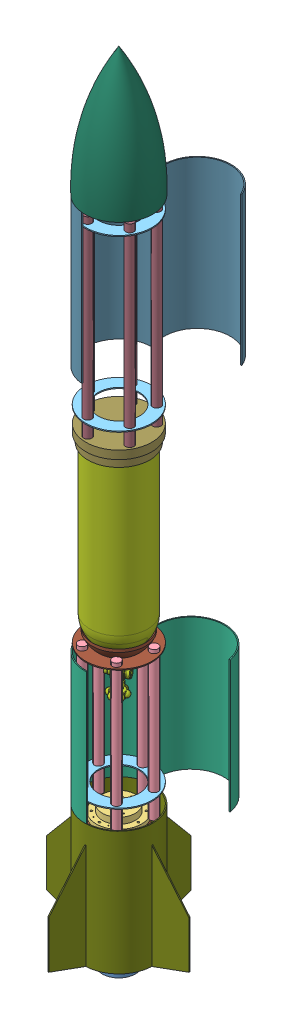
SolidWorks assembly Frame Assembly, configuration Default. Lengths in mm.
Overall size (438.15 2452.29 506.31).
43 component instances, 18 part files, 47 mates.
Components (placement in the parent):
- Nozzle-1: Nozzle [Default] at (-18.8672 -125.1842 41.6803) x (0 -1 0) z (0 0 1) size (105.37 139.7 139.7)
- Current Combustion Chamber Design-1: Current Combustion Chamber Design [Default] at (-18.8672 -92.1369 41.6803) x (0.707107 0 0.707107) z (-0.707107 0 0.707107) size (139.7 292.1 139.7)
- Injector EXP9A with holes for slide hammer mount-1: Injector EXP9A with holes for slide hammer mount [Default] at (-18.8672 199.9631 41.6803) size (139.7 46.35 139.7)
- Injector EXP9A Gas Director-1: Injector EXP9A Gas Director [Default] at (-298.3277 71.3556 111.278) x (0 1 0) z (0 0 1) (suppressed, hidden)
- SupportRod-1: SupportRod [Default] at (-26.6307 213.5078 -40.5038) x (-0.151933 0 0.988391) z (-0.988391 0 -0.151933) size (25.4 457.2 25.4)
- SupportRod-2: SupportRod [Default] at (-99.428 216.632 23.6675) x (-0.999256 0 0.038575) z (-0.038575 0 -0.999256) size (25.4 457.2 25.4)
- SupportRod-3: SupportRod [Default] at (56.8955 216.4117 8.9005) x (0.333023 0 0.942919) z (-0.942919 0 0.333023) size (25.4 457.2 25.4)
- SupportRod-4: SupportRod [Default] at (35.7201 216.8857 103.6054) x (-0.29911 0 -0.954219) z (0.954219 0 -0.29911) size (25.4 457.2 25.4)
- SeperationPlate-1: SeperationPlate [Default] at (-18.8672 288.5483 41.6803) x (0.218205 0 -0.975903) z (0.975903 0 0.218205) size (203.2 3.17 203.2)
- SupportRod-5: SupportRod [Default] at (-60.8931 217.2601 112.7319) x (0.784034 0 0.620718) z (-0.620718 0 0.784034) size (25.4 457.2 25.4)
- CompositeFrameExteriorStructure24in-1: CompositeFrameExteriorStructure24in [Default] at (-18.8672 232.3162 41.6803) x (0.999056 0 -0.043441) z (0.043441 0 0.999056) size (104.77 406.4 209.55)
- NITROGEN D CYLINDER-1: NITROGEN D CYLINDER [Default] at (-18.8672 1217.5191 41.6803) x (-0.858895 0 0.512152) z (0.512152 0 0.858895) size (177.6 693.58 177.6)
- 428501-1: 428501 [Default] at (-15.3433 588.5535 -74.8912) x (-0.824485 0 -0.565883) z (0 -1 0) size (37.82 30.4 40)
  - 428501_01-1: 428501_01 [Default] at (0.4388 -14.7465 7.9373) size (4 4 40)
  - 428501_02-1: 428501_02 [Default] at (3.1323 -14.0418 7.9373) x (0.871871 0.489735 0) z (0 0 1) size (25 9 40)
  - 428501_03-1: 428501_03 [Default] at (4.0636 -13.383 7.9373) x (0.752088 0.659062 0) z (0 0 1) size (25 9 40)
- 428501-2: 428501 [Default] at (-11.8931 309.2254 -65.5442) x (-0.259076 0 0.965857) z (0 1 0) size (37.82 30.4 40)
  - 428501_01-1: 428501_01 [Default] at (0.4388 -14.7465 7.9373) size (4 4 40)
  - 428501_02-1: 428501_02 [Default] at (3.1323 -14.0418 7.9373) x (0.871871 0.489735 0) z (0 0 1) size (25 9 40)
  - 428501_03-1: 428501_03 [Default] at (4.0636 -13.383 7.9373) x (0.752088 0.659062 0) z (0 0 1) size (25 9 40)
- NozTankCrown-1: NozTankCrown [Default] at (-18.8672 662.9088 41.6803) x (0.86071 0 0.509096) z (0.509096 0 -0.86071) size (203.2 42.97 203.2)
- CompositeFrameExteriorFull36in-1: CompositeFrameExteriorFull36in [Default] at (-18.8672 638.7162 41.6803) x (-0.047455 0 -0.998873) z (0.998873 0 -0.047455) size (209.55 762 209.55) (hidden)
- NozTankAssCrown-1: NozTankAssCrown [Default] at (-18.8672 1222.2309 41.6803) x (-0.13558 0 -0.990766) z (-0.990766 0 0.13558) size (203.2 50.8 203.2)
- SupportRod24in-1: SupportRod24in [Default] at (-100.655 1232.4164 52.8724) x (0.999852 0 -0.017197) z (0.017197 0 0.999852) size (25.4 609.6 25.4)
- SupportRod24in-2: SupportRod24in [Default] at (-33.4967 1231.366 122.9236) x (0.936344 0 -0.351085) z (0.351085 0 0.936344) size (25.4 609.6 25.4)
- SupportRod24in-3: SupportRod24in [Default] at (-54.7854 1237.8941 -32.6459) x (0.492864 0 0.870106) z (-0.870106 0 0.492864) size (25.4 609.6 25.4)
- SupportRod24in-4: SupportRod24in [Default] at (40.7219 1230.4275 -15.4479) x (0.999381 0 0.035175) z (-0.035175 0 0.999381) size (25.4 609.6 25.4)
- SupportRod24in-5: SupportRod24in [Default] at (53.879 1234.6808 80.6994) x (-0.025982 0 -0.999662) z (0.999662 0 -0.025982) size (25.4 609.6 25.4)
- SeperationPlate-2: SeperationPlate [Default] at (-18.8672 1817.5879 41.6803) x (0.692044 0 0.721855) z (-0.721855 0 0.692044) size (203.2 3.17 203.2)
- CompositeFrameExteriorStructure-1: CompositeFrameExteriorStructure [Default] at (-18.8672 1400.7162 41.6803) x (0.995236 0 0.097497) z (-0.097497 0 0.995236) size (104.77 457.2 209.55)
- CompositeFrameExteriorStructure-2: CompositeFrameExteriorStructure [Default] at (73.7396 1400.7162 -107.6521) x (0.399351 0 0.916798) z (-0.916798 0 0.399351) size (104.77 457.2 209.55)
- 428501-3: 428501 [Default] at (-10.6915 1782.3535 -76.3779) x (-0.999889 0 -0.014888) z (0 -1 0) size (37.82 30.4 40)
  - 428501_01-1: 428501_01 [Default] at (0.4388 -14.7465 7.9373) size (4 4 40)
  - 428501_02-1: 428501_02 [Default] at (3.1323 -14.0418 7.9373) x (0.871871 0.489735 0) z (0 0 1) size (25 9 40)
  - 428501_03-1: 428501_03 [Default] at (4.0636 -13.383 7.9373) x (0.752088 0.659062 0) z (0 0 1) size (25 9 40)
- 428501-4: 428501 [Default] at (-10.6915 1473.4424 -76.3779) x (-0.999889 0 -0.014888) z (0 -1 0) size (37.82 30.4 40)
  - 428501_01-1: 428501_01 [Default] at (0.4388 -14.7465 7.9373) size (4 4 40)
  - 428501_02-1: 428501_02 [Default] at (3.1323 -14.0418 7.9373) x (0.871871 0.489735 0) z (0 0 1) size (25 9 40)
  - 428501_03-1: 428501_03 [Default] at (4.0636 -13.383 7.9373) x (0.752088 0.659062 0) z (0 0 1) size (25 9 40)
- DumbassNoseCone-1: DumbassNoseCone [Default] at (-18.8672 1857.9162 41.6803) x (0.981984 0 0.188962) z (-0.188962 0 0.981984) size (215.74 396.86 215.74)
- DumbassBase-1: DumbassBase [Default] at (-18.8672 -148.6838 41.6803) size (438.15 381 438.15)
- CompositeFrameExteriorStructure24in-3: CompositeFrameExteriorStructure24in [Default] at (72.3445 232.3162 -89.3974) x (0.171523 0 0.98518) z (-0.98518 0 0.171523) size (104.77 406.4 209.55)
- SeperationPlate-3: SeperationPlate [Default] at (-18.8672 1295.1978 41.6803) x (0.692044 0 0.721855) z (-0.721855 0 0.692044) size (203.2 3.17 203.2)
Mates (geometry in assembly coordinates):
- Concentric1: concentric: circle of Nozzle-1; circle of Current Combustion Chamber Design-1
- Coincident1: coincident: circle of Nozzle-1; circle of Current Combustion Chamber Design-1
- Concentric2: concentric: circle of Injector EXP9A with holes for slide hammer mount-1; circle of Injector EXP9A Gas Director-1
- Distance1: distance = 0.0127 mm: plane of Injector EXP9A Gas Director-1 through (-298.3277 71.3556 111.278) normal (1 0 0); plane of Injector EXP9A with holes for slide hammer mount-1
- Concentric3: concentric: circle of Current Combustion Chamber Design-1; circle of Injector EXP9A with holes for slide hammer mount-1
- Coincident3: coincident: circle of Current Combustion Chamber Design-1; circle of Injector EXP9A with holes for slide hammer mount-1
- Concentric4: concentric: circle of Injector EXP9A with holes for slide hammer mount-1; circle of SeperationPlate-1
- Concentric5: concentric: circle of SupportRod-1; circle of SeperationPlate-1
- Concentric6: concentric: circle of SupportRod-2; circle of SeperationPlate-1
- Concentric7: concentric: circle of SupportRod-3; circle of SeperationPlate-1
- Concentric8: concentric: circle of SupportRod-4; circle of SeperationPlate-1
- Concentric9: concentric: circle of SeperationPlate-1; circle of SupportRod-5
- Concentric15: concentric: circle of Injector EXP9A with holes for slide hammer mount-1; circle of NITROGEN D CYLINDER-1
- Concentric18: concentric: circle of NITROGEN D CYLINDER-1; circle of NozTankCrown-1
- Concentric19: concentric: circle of SupportRod-5; circle of NozTankCrown-1
- Concentric20: concentric: circle of SupportRod-3; circle of NozTankCrown-1
- Concentric21: concentric: circle of CompositeFrameExteriorStructure24in-1; circle of NozTankCrown-1
- Concentric23: concentric: circle of NITROGEN D CYLINDER-1; circle of CompositeFrameExteriorFull36in-1
- Concentric24: concentric: circle of NITROGEN D CYLINDER-1; circle of NozTankAssCrown-1
- Concentric25: concentric: circle of NozTankAssCrown-1; circle of SupportRod24in-1
- Concentric26: concentric: circle of NozTankAssCrown-1; circle of SupportRod24in-2
- Concentric27: concentric: circle of NozTankAssCrown-1; circle of SupportRod24in-3
- Concentric28: concentric: circle of NozTankAssCrown-1; circle of SupportRod24in-4
- Concentric29: concentric: circle of NozTankAssCrown-1; circle of SupportRod24in-5
- Concentric30: concentric: circle of SupportRod24in-3; circle of SeperationPlate-2
- Concentric31: concentric: circle of SupportRod24in-2; circle of SeperationPlate-2
- Concentric32: concentric: circle of SeperationPlate-2; circle of CompositeFrameExteriorStructure-1
- Concentric34: concentric: circle of CompositeFrameExteriorStructure-1; circle of DumbassNoseCone-1
- Concentric33: concentric: circle of CompositeFrameExteriorStructure24in-1; circle of DumbassBase-1
- Coincident4: coincident: line of CompositeFrameExteriorStructure24in-1 through (-23.2808 638.7162 -59.8238) axis (0 -1 0); line of 428501-1/428501_02-1 through (-23.2808 590.6162 -59.8238) axis (0 1 0)
- Coincident6: coincident: line of CompositeFrameExteriorStructure24in-1 through (-23.2808 638.7162 -59.8238) axis (0 -1 0); line of 428501-2/428501_03-1 through (-23.2808 327.1627 -59.8238) axis (0 1 0)
- Coincident9: coincident: line of CompositeFrameExteriorStructure-1 through (-8.9615 1857.9162 -59.4357) axis (0 -1 0); line of 428501-3/428501_02-1 through (-8.9615 1784.4162 -59.4357) axis (0 1 0)
- Coincident10: coincident: line of CompositeFrameExteriorStructure-2 through (-19.4071 1857.9162 -67.078) axis (0 -1 0); line of 428501-3/428501_03-1 through (-19.4071 1794.4162 -67.078) axis (0 -1 0)
- Coincident11: coincident: line of CompositeFrameExteriorStructure-1 through (-8.9615 1857.9162 -59.4357) axis (0 -1 0); line of 428501-4/428501_02-1 through (-8.9615 1475.5051 -59.4357) axis (0 1 0)
- Coincident12: coincident: line of CompositeFrameExteriorStructure-2 through (-19.4071 1857.9162 -67.078) axis (0 -1 0); line of 428501-4/428501_03-1 through (-19.4071 1485.5051 -67.078) axis (0 -1 0)
- Coincident13: coincident: plane of CompositeFrameExteriorStructure24in-1 through (-18.8672 232.3162 41.6803) normal (0 -1 0); plane of DumbassBase-1 through (-18.8672 232.3162 41.6803) normal (0 1 0)
- Coincident14: coincident: plane of CompositeFrameExteriorStructure24in-1 through (-18.8672 638.7162 41.6803) normal (0 1 0); plane of CompositeFrameExteriorFull36in-1 through (-18.8672 638.7162 41.6803) normal (0 -1 0)
- Coincident16: coincident: plane of CompositeFrameExteriorFull36in-1 through (-18.8672 1400.7162 41.6803) normal (0 1 0); plane of CompositeFrameExteriorStructure-1 through (-18.8672 1400.7162 41.6803) normal (0 -1 0)
- Coincident17: coincident: plane of CompositeFrameExteriorStructure-1 through (-18.8672 1857.9162 41.6803) normal (0 1 0); plane of DumbassNoseCone-1 through (-118.6369 1857.9162 22.4818) normal (0 -1 0)
- Coincident30: coincident: line of 428501-1/428501_03-1 through (-27.7498 600.6162 -71.9706) axis (0 -1 0); line of CompositeFrameExteriorStructure24in-3 through (-27.7498 638.7162 -71.9706) axis (0 -1 0)
- Coincident31: coincident: line of 428501-2/428501_02-1 through (-27.7498 337.1627 -71.9706) axis (0 -1 0); line of CompositeFrameExteriorStructure24in-3 through (-27.7498 638.7162 -71.9706) axis (0 -1 0)
- Distance11: distance = 63.5 mm: plane of 428501-3/428501_02-1 through (-14.0326 1794.4162 -62.3843) normal (0 1 0); plane of CompositeFrameExteriorStructure-2 through (73.7396 1857.9162 -107.6521) normal (0 1 0)
- Distance12: distance = 63.5 mm: plane of DumbassNoseCone-1 through (-118.6369 1857.9162 22.4818) normal (0 -1 0); plane of 428501-3/428501_03-1 through (-14.954 1794.4162 -63.0569) normal (0 1 0)
- Distance13: distance = 38.1 mm: plane of 428501-1/428501_02-1 through (-25.8719 600.6162 -65.0865) normal (0 1 0); plane of CompositeFrameExteriorStructure24in-3 through (72.3445 638.7162 -89.3974) normal (0 1 0)
- Distance14: distance = 38.1 mm: plane of CompositeFrameExteriorFull36in-1 through (-18.8672 638.7162 41.6803) normal (0 -1 0); plane of 428501-1/428501_03-1 through (-26.267 600.6162 -66.1567) normal (0 1 0)
- Concentric35: concentric: circle of SupportRod24in-5; circle of SeperationPlate-3
- Concentric36: concentric: circle of SupportRod24in-3; circle of SeperationPlate-3
